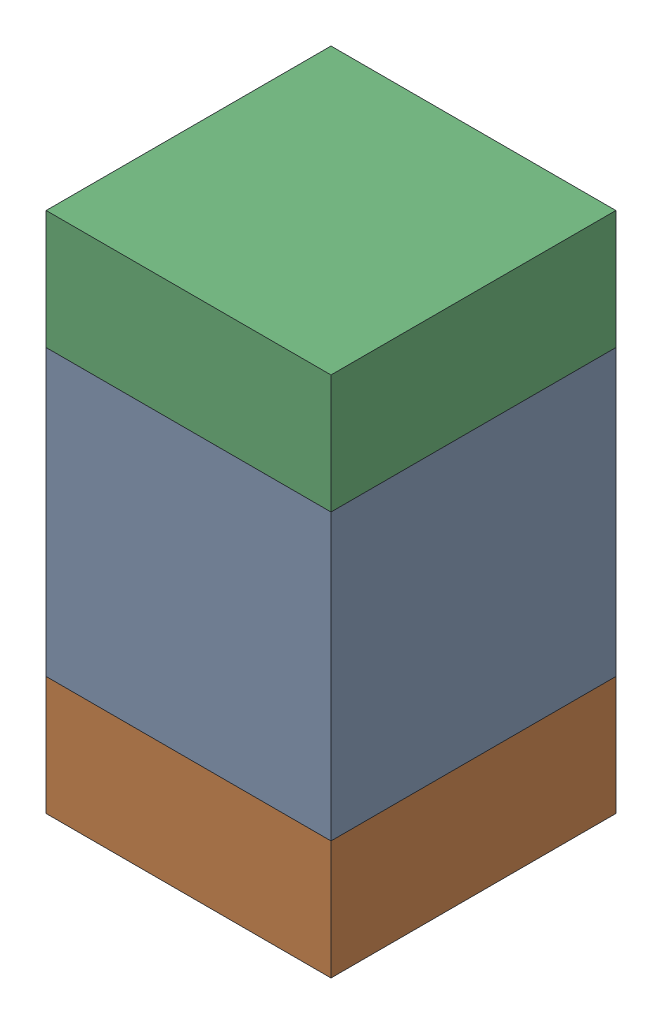
SolidWorks assembly C306_1PCB, configuration Default. Lengths in mm.
Overall size (0.6 1.1 0.6).
6 component instances, 2 part files, 0 mates.
Components (placement in the parent):
- 761606048-1: 761606048 [Default] at (130.2 108 0) size (0.6 0.6 0.6)
  - Extruded_9-1: Extruded_9 [Default] at origin size (0.6 0.6 0.6)
- 854785296-1: 854785296 [Default] at (130.2 107.575 0) size (0.6 0.25 0.6)
  - Extruded_10-1: Extruded_10 [Default] at origin size (0.6 0.25 0.6)
- 854785296-2: 854785296 [Default] at (130.2 108.425 0) size (0.6 0.25 0.6)
  - Extruded_10-1: Extruded_10 [Default] at origin size (0.6 0.25 0.6)
